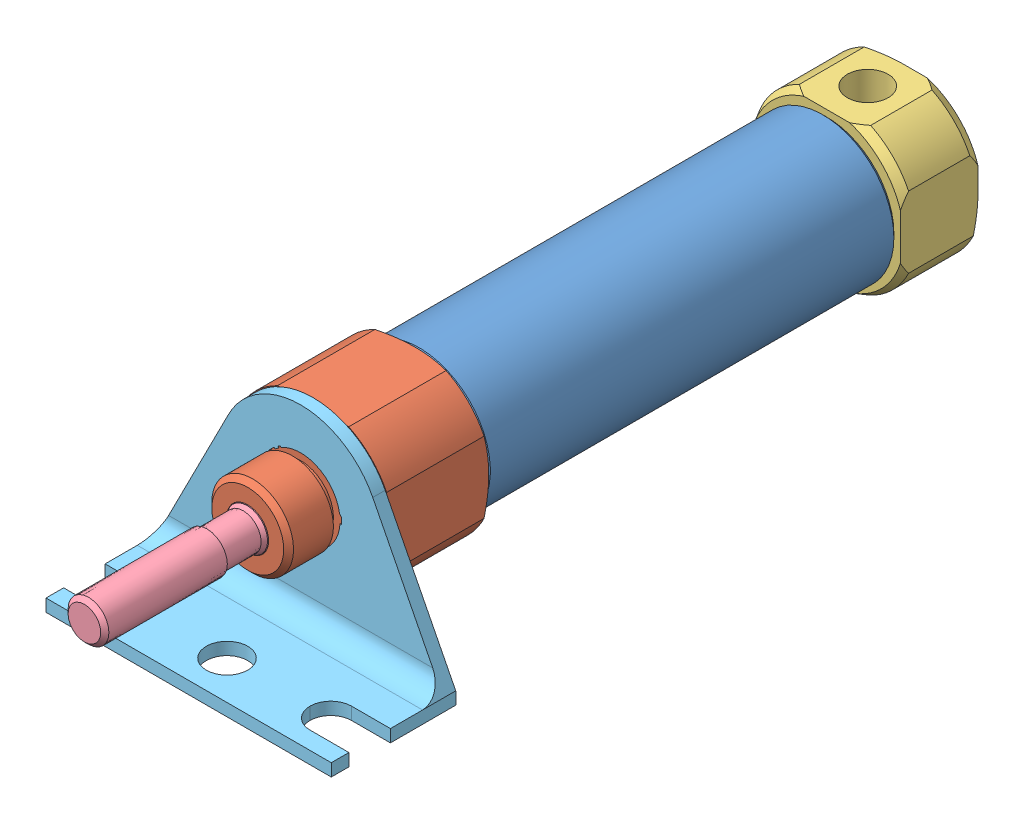
SolidWorks assembly NCJ22005Z-MP, configuration Default. Lengths in mm.
Overall size (34.92 23.88 100.4).
5 component instances, 5 part files, 15 mates.
Components (placement in the parent):
- NCJ2Tubes-1: NCJ2Tubes [16] at origin size (17.4 17.4 50.4)
- NCJ2RodCover-1: NCJ2RodCover [16] at (0 0 25.2) size (18 18 20.5)
- NCJ2HeadCover-1: NCJ2HeadCover [16] at (0 0 -34.7) size (18 18 9.5)
- NCJ2Rods-1: NCJ2Rods [16] at (0 0 -12.7) size (15.5 15.5 80.9)
- pneumatic-cylinder-bracket-1: pneumatic-cylinder-bracket [Default] at (0 -13.97 37.7) size (34.92 23.88 15.24)
Mates (geometry in assembly coordinates):
- Parallel1: parallel aligned: plane of NCJ2RodCover-1; plane of assembly
- Concentric2: concentric aligned: cylinder of NCJ2Tubes-1 through (0 0 25.2) axis (0 0 -1) radius 8.7; cylinder of NCJ2HeadCover-1 through (0 0 -25.2) axis (0 0 -1) radius 10
- Parallel2: parallel aligned: plane of NCJ2HeadCover-1; plane of assembly
- Coincident1: coincident anti-aligned: plane of NCJ2Tubes-1 through (0 0 25.2) normal (0 0 1); plane of NCJ2RodCover-1 through (0 0 25.2) normal (0 0 -1)
- Coincident2: coincident anti-aligned: plane of NCJ2Tubes-1 through (0 0 -25.2) normal (0 0 -1); plane of NCJ2HeadCover-1 through (0 0 -25.2) normal (0 0 1)
- Concentric9: concentric aligned: cylinder of NCJ2Tubes-1 through (0 0 25.2) axis (0 0 -1) radius 8.7; cylinder of NCJ2Rods-1 through (0 0 46.27) axis (0 0 -1) radius 2.5
- Stroke Distance: distance = 0 mm anti-aligned: plane of NCJ2Tubes-1 through (0 0 -15.2) normal (0 0 1); plane of NCJ2Rods-1 through (0 0 -15.2) normal (0 0 -1)
- Parallel9: parallel aligned: plane of NCJ2Rods-1; plane of assembly
- Concentric11: concentric aligned: cylinder of NCJ2Tubes-1 through (0 0 25.2) axis (0 0 -1) radius 8.7; cylinder of NCJ2RodCover-1 through (0 0 37.7) axis (0 0 -1) radius 10
- Distance13: distance = 0 mm anti-aligned: plane of NCJ2RodCover-1 through (0 0 37.7) normal (0 0 1); plane of ?
- Concentric18: concentric anti-aligned: cylinder of NCJ2Tubes-1 through (0 0 49.8073) axis (0 0 -1) radius 8.7; cylinder of assembly through (0 0 40) axis (0 0 1) radius 5
- Parallel14: parallel aligned: plane of NCJ2RodCover-1 through (-4.3589 9 37.7) normal (0 1 0); plane of ?
- Concentric19: concentric aligned: cylinder of NCJ2RodCover-1 through (0 0 45.7) axis (0 0 -1) radius 5; cylinder of pneumatic-cylinder-bracket-1 through (0 0 39.224) axis (0 0 -1) radius 4.826
- Coincident3: coincident anti-aligned: plane of NCJ2RodCover-1 through (0 0 37.7) normal (0 0 1); plane of pneumatic-cylinder-bracket-1 through (0 0 37.7) normal (0 0 -1)
- Parallel15: parallel aligned: plane of NCJ2RodCover-1 through (-4.3589 9 37.7) normal (0 1 0); plane of pneumatic-cylinder-bracket-1 through (-17.4625 -12.446 52.94) normal (0 1 0)
